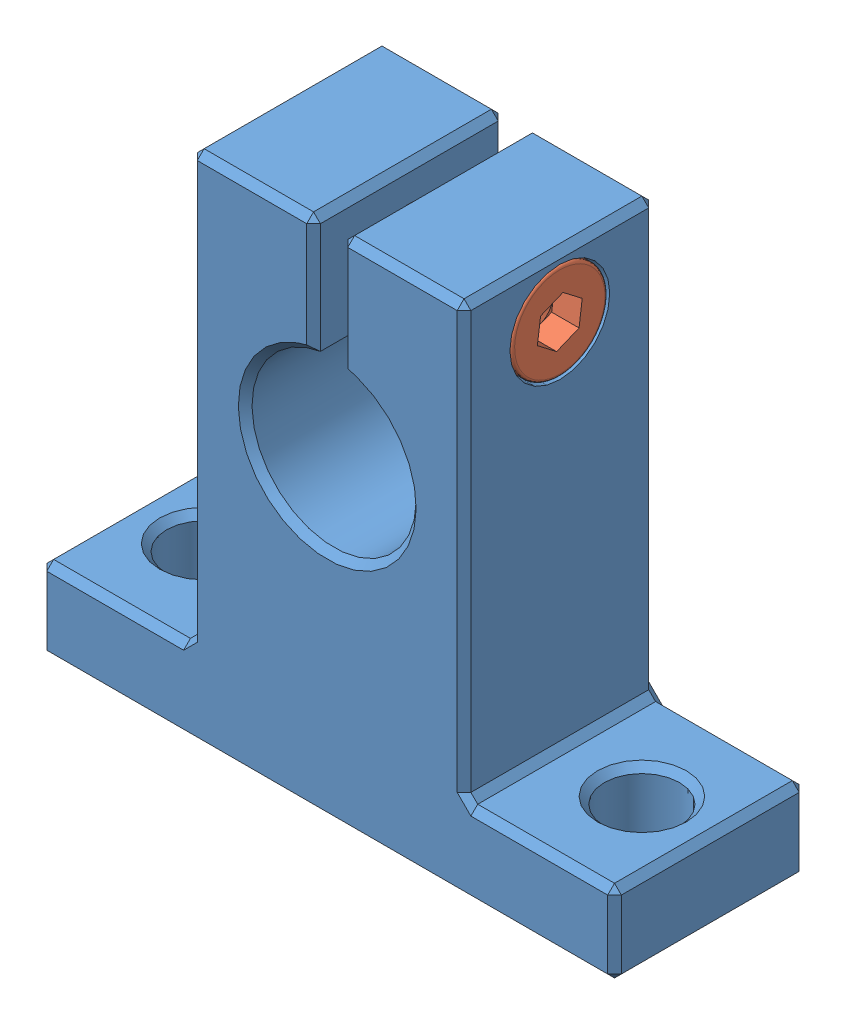
SolidWorks assembly Suporte_SK12, configuration Valor predeterminado. Lengths in mm.
Overall size (42 37.6 14).
2 component instances, 2 part files, 2 mates.
Components (placement in the parent):
- Shaft support SK12-1: Shaft support SK12 [Valor predeterminado] at (-5.6953 6.0163 42) size (42 37.5 14)
- m4x16-2: m4x16 [Valor predeterminado] at (4.3047 16.0441 42) x (-1 0 0) z (0 0.924225 0.381849) size (20 7 7)
Mates (geometry in assembly coordinates):
- Concêntrico11: concentric aligned: cylinder of Shaft support SK12-1 through (4.3047 16.0441 42) axis (1 0 0) radius 3.65; cylinder of m4x16-2 through (0.3047 16.0441 42) axis (1 0 0) radius 3.5
- Coincidente11: coincident anti-aligned: plane of Shaft support SK12-1 through (0.3047 17.7441 42) normal (1 0 0); plane of m4x16-2 through (0.3047 14.7076 45.2348) normal (-1 0 0)
